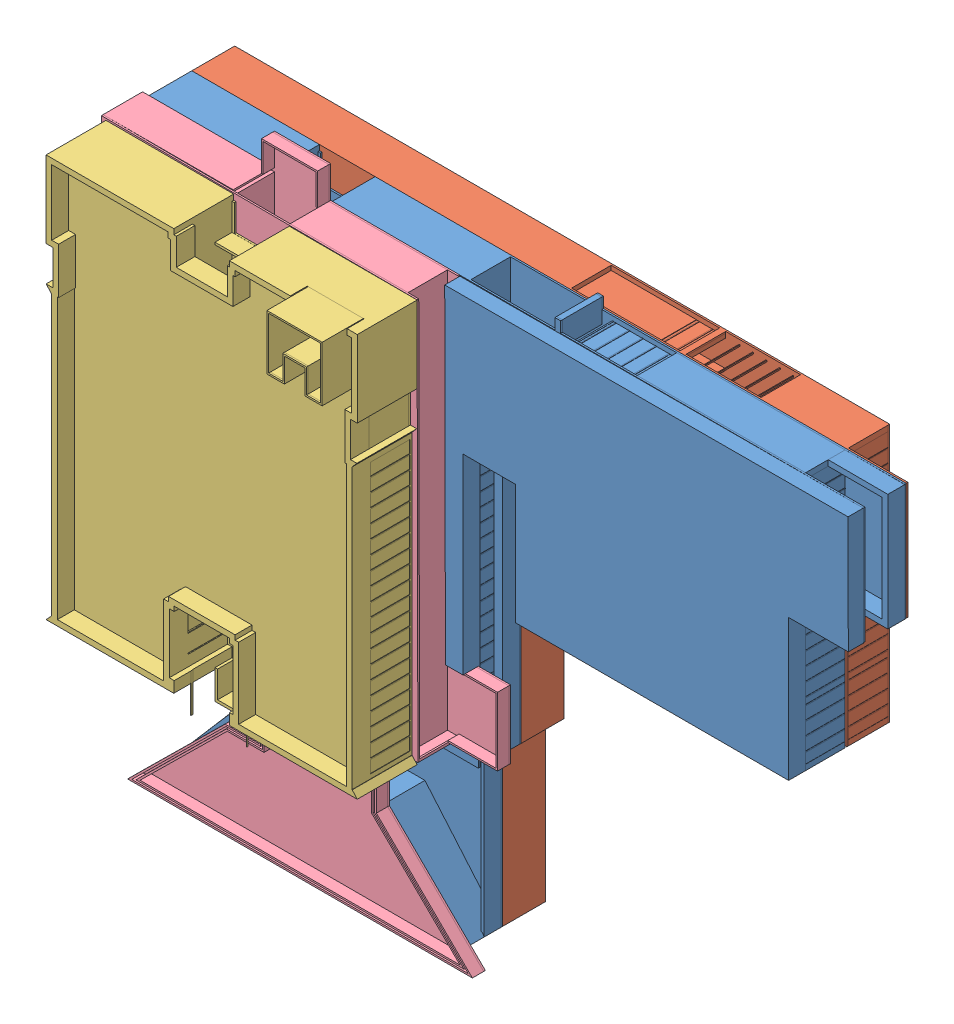
SolidWorks assembly CNyNEdificioC, configuration Default. Lengths in mm.
Overall size (185201.33 74545.95 18850).
4 component instances, 4 part files, 9 mates.
Components (placement in the parent):
- EdicioCPiso0-2: EdicioCPiso0 [Predeterminado] at (-78017.8177 -31741.8521 109750) size (111500 74333.33 7450)
- EdicioCPiso-1-2: EdicioCPiso-1 [Predeterminado] at (-78017.8177 -31741.8521 105950) size (185201.33 74333.33 3800)
- EdicioCPiso2-2: EdicioCPiso2 [Predeterminado] at (-78017.8177 -31741.8521 117350) size (77230 61983.22 7450)
- EdificioCPiso1Ciceli-1: EdificioCPiso1Ciceli [Predeterminado] at (-76749.0709 -31746.4921 113550) size (66633.82 67712.56 3800)
Mates (geometry in assembly coordinates):
- Coincidente9: coincident anti-aligned: plane of EdicioCPiso0-2 through (-78017.8177 -31741.8521 109600) normal (0 0 -1); plane of EdicioCPiso-1-2 through (-78017.8177 -31741.8521 109600) normal (0 0 1)
- Coincidente10: coincident aligned: line of EdicioCPiso0-2 through (-22627.0291 16949.5639 109600) axis (0 1 0); line of EdicioCPiso-1-2 through (-22627.0291 16949.5639 109600) axis (0 1 0)
- Coincidente11: coincident: point of EdicioCPiso0-2; point of EdicioCPiso-1-2
- Coincidente27: coincident anti-aligned: plane of EdicioCPiso0-2 through (-78017.8177 -31741.8521 113400) normal (0 0 1); plane of EdificioCPiso1Ciceli-1 through (-76749.0709 -31746.4921 113400) normal (0 0 -1)
- Coincidente28: coincident anti-aligned: line of EdicioCPiso0-2 through (-44221.888 19668.9821 113400) axis (0 -1 0); line of EdificioCPiso1Ciceli-1 through (-44221.888 15078.9821 113400) axis (0 1 0)
- Coincidente30: coincident: point of EdicioCPiso0-2; point of EdificioCPiso1Ciceli-1
- Coincidente31: coincident anti-aligned: plane of EdicioCPiso2-2 through (-78017.8177 -31741.8521 117200) normal (0 0 -1); plane of EdificioCPiso1Ciceli-1 through (-76749.0709 -31746.4921 117200) normal (0 0 1)
- Coincidente32: coincident anti-aligned: line of EdicioCPiso2-2 through (-44221.888 19668.9821 117200) axis (0 -1 0); line of EdificioCPiso1Ciceli-1 through (-44221.888 15078.9821 117200) axis (0 1 0)
- Coincidente33: coincident: point of EdicioCPiso2-2; point of EdificioCPiso1Ciceli-1
